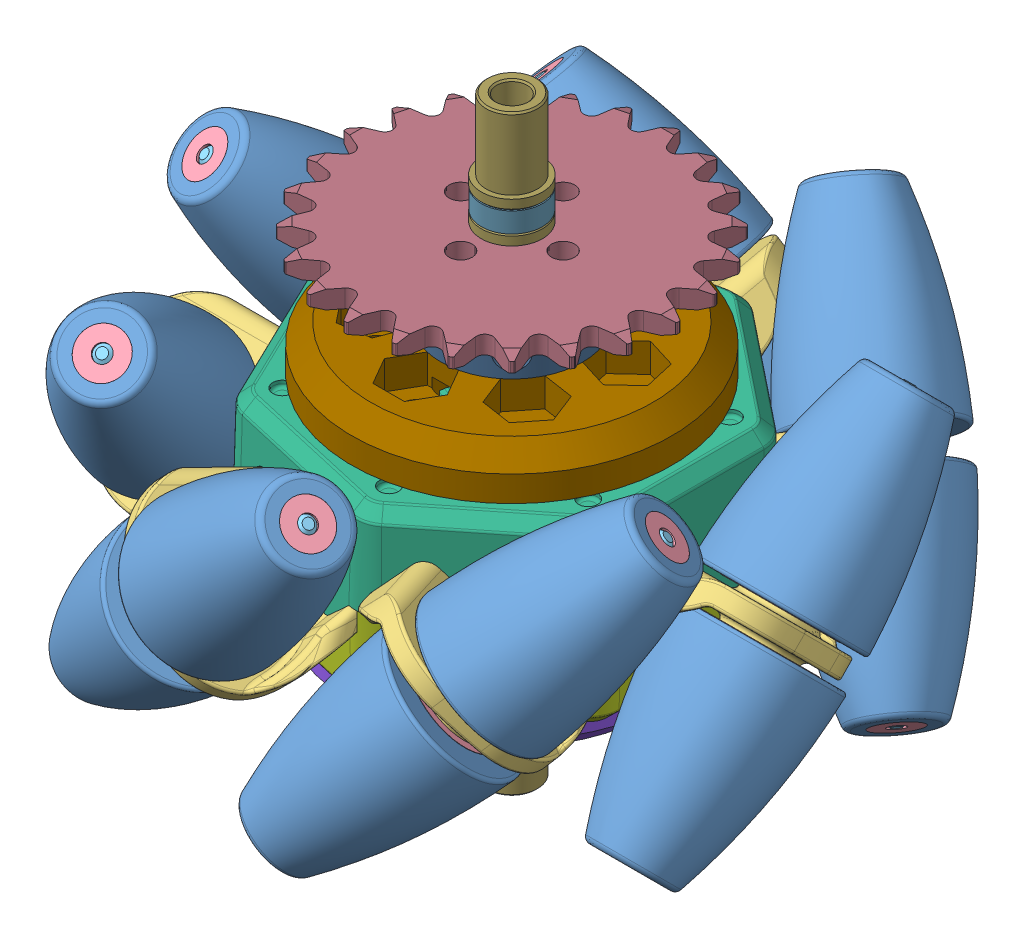
SolidWorks assembly Mecanum Left Assembly, configuration Default. Lengths in mm.
Overall size (116.24 92.45 118.47).
72 component instances, 14 part files, 18 mates.
Components (placement in the parent):
- Mecanum Left-1: Mecanum Left [Default] at (35.1717 68.1525 91.4485) size (116.24 62.26 118.47)
  - Roller-1: Roller [Default] at (-8.8714 -0.1061 -39.3041) x (-0.709843 -0.615883 -0.341777) z (0.144671 0.347402 -0.926489) size (22.31 28.6 22.31)
  - Washer-1: Washer [Default] at (-2.1949 -6.9473 -40.8283) x (-0.689398 -0.707107 0.15726) z (0.68937 -0.707107 -0.15738) size (6 6 6.25)
  - Bracket Left-1: Bracket Left [Default] at origin size (28.34 25.51 28.03)
  - Roller Hub-2: Roller Hub [Default] at (25.0439 -0.1061 31.5645) x (0.446415 -0.698084 -0.559815) z (0.703674 -0.112601 0.701544) size (15.2 28.65 15.2)
  - Pin-1: Pin [Default] at (40.2927 0.0354 -0.0424) x (0.491193 -0.615883 -0.615969) z (0.871051 0.347402 0.34725) size (2.6 61.8 2.6)
  - Roller-3: Roller [Default] at (-36.2516 0.1061 17.5878) x (-0.306866 0.707107 -0.637051) z (-0.900888 0.000087 0.434052) size (22.31 28.6 22.31)
  - Washer-2: Washer [Default] at (19.6895 6.9473 -35.8342) x (-0.552772 -0.707107 -0.440957) z (0.552849 -0.707107 0.44086) size (6 6 6.25)
  - Roller-5: Roller [Default] at (25.1987 -0.1061 -31.441) x (-0.175349 -0.615883 -0.768076) z (0.814571 0.347402 -0.464528) size (22.31 28.6 22.31)
  - Washer-5: Washer [Default] at (-33.2899 -6.9473 -23.7392) x (-0.306866 -0.707107 0.637051) z (0.306754 -0.707107 -0.637104) size (6 6 6.25)
  - Bracket Left-2: Bracket Left [Default] x (0.62347 0 -0.781847) z (0.781847 0 0.62347) size (28.34 25.51 28.03)
  - Pin-2: Pin [Default] at (25.1544 0.0354 31.4763) x (0.787838 -0.615883 0) z (0.271578 0.347402 0.897528) size (2.6 61.8 2.6)
  - Roller-6: Roller [Default] at (-36.3528 0.1061 -17.3777) x (0.306754 0.707107 -0.637104) z (-0.901039 0.000087 -0.433738) size (22.31 28.6 22.31)
  - Washer-6: Washer [Default] at (-15.741 6.9473 -37.7357) x (-0.689398 -0.707107 0.15726) z (0.68937 -0.707107 -0.15738) size (6 6 6.25)
  - Roller-9: Roller [Default] at (40.2927 -0.1061 0.099) x (0.491193 -0.615883 -0.615969) z (0.871051 0.347402 0.34725) size (22.31 28.6 22.31)
  - Washer-8: Washer [Default] at (-39.3157 -6.9473 11.2269) x (0.306754 -0.707107 0.637104) z (-0.306866 -0.707107 -0.637051) size (6 6 6.25)
  - Bracket Left-3: Bracket Left [Default] x (-0.22257 0 -0.974917) z (0.974917 0 -0.22257) size (28.34 25.51 28.03)
  - Bracket Left-4: Bracket Left [Default] x (-0.901001 0 -0.433816) z (0.433816 0 -0.901001) size (28.34 25.51 28.03)
  - Roller Hub-6: Roller Hub [Default] at (-36.2516 0.1061 17.5878) x (-0.446512 0.698084 -0.559737) z (-0.840471 -0.112601 0.530028) size (15.2 28.65 15.2)
  - Roller-10: Roller [Default] at (-9.0782 0.1061 -39.2568) x (0.68937 0.707107 -0.15738) z (-0.222655 0.000087 -0.974897) size (22.31 28.6 22.31)
  - Washer-10: Washer [Default] at (-39.3176 6.9473 -11.2201) x (-0.306866 -0.707107 0.637051) z (0.306754 -0.707107 -0.637104) size (6 6 6.25)
  - Roller-13: Roller [Default] at (25.0439 -0.1061 31.5645) x (0.787838 -0.615883 0) z (0.271578 0.347402 0.897528) size (22.31 28.6 22.31)
  - Washer-11: Washer [Default] at (-15.7344 -6.9473 37.7385) x (0.68937 -0.707107 0.15738) z (-0.689398 -0.707107 -0.15726) size (6 6 6.25)
  - Bracket Left-5: Bracket Left [Default] x (-0.900926 0 0.433974) z (-0.433974 0 -0.900926) size (28.34 25.51 28.03)
  - Roller Hub-8: Roller Hub [Default] at (-36.3437 -0.1061 17.3967) x (0.446512 -0.698084 0.559737) z (-0.840471 -0.112601 0.530028) size (15.2 28.65 15.2)
  - Roller-14: Roller [Default] at (25.0329 0.1061 -31.5732) x (0.552849 0.707107 0.44086) z (0.623402 0.000087 -0.781901) size (22.31 28.6 22.31)
  - Washer-14: Washer [Default] at (-33.2858 6.9473 23.745) x (0.306754 -0.707107 0.637104) z (-0.306866 -0.707107 -0.637051) size (6 6 6.25)
  - Roller Hub-11: Roller Hub [Default] at (25.1987 -0.1061 -31.441) x (-0.645131 -0.698084 -0.310619) z (0.527331 -0.112601 -0.842166) size (15.2 28.65 15.2)
  - Roller Hub-12: Roller Hub [Default] at (25.0329 0.1061 -31.5732) x (0.645131 0.698084 0.310619) z (0.527331 -0.112601 -0.842166) size (15.2 28.65 15.2)
  - Pin-5: Pin [Default] at (-8.9197 0.0354 39.293) x (0.491301 -0.615883 0.615883) z (-0.532275 0.347402 0.772007) size (2.6 61.8 2.6)
  - Washer-15: Washer [Default] at (19.6958 -6.9473 35.8307) x (0.552849 -0.707107 -0.44086) z (-0.552772 -0.707107 0.440957) size (6 6 6.25)
  - Bracket Left-6: Bracket Left [Default] x (-0.222399 0 0.974956) z (-0.974956 0 -0.222399) size (28.34 25.51 28.03)
  - Roller Hub-13: Roller Hub [Default] at (40.2927 -0.1061 0.099) x (-0.159363 -0.698084 -0.698056) z (0.98722 -0.112601 -0.112773) size (15.2 28.65 15.2)
  - Roller Hub-14: Roller Hub [Default] at (-36.3528 0.1061 -17.3777) x (0.159242 0.698084 -0.698084) z (-0.938409 -0.112601 -0.326663) size (15.2 28.65 15.2)
  - Roller-17: Roller [Default] at (40.2927 0.1061 -0.1131) x (0 0.707107 0.707107) z (1 0.000087 -0.000087) size (22.31 28.6 22.31)
  - Washer-17: Washer [Default] at (-2.1877 6.9473 40.8287) x (0.68937 -0.707107 0.15738) z (-0.689398 -0.707107 -0.15726) size (6 6 6.25)
  - Roller Hub-17: Roller Hub [Default] at (40.2927 0.1061 -0.1131) x (0.159363 0.698084 0.698056) z (0.98722 -0.112601 -0.112773) size (15.2 28.65 15.2)
  - Pin-7: Pin [Default] at (-36.2823 0.0354 17.5241) x (-0.175215 -0.615883 0.768107) z (-0.935449 0.347402 0.065166) size (2.6 61.8 2.6)
  - Washer-19: Washer [Default] at (40.2939 -6.9473 6.9403) x (0 -0.707107 -0.707107) z (0.000123 -0.707107 0.707107) size (6 6 6.25)
  - Bracket Left-7: Bracket Left [Default] x (0.623607 0 0.781738) z (-0.781738 0 0.623607) size (28.34 25.51 28.03)
  - Roller Hub-18: Roller Hub [Default] at (-36.2608 -0.1061 -17.5689) x (-0.159242 -0.698084 0.698084) z (-0.938409 -0.112601 -0.326663) size (15.2 28.65 15.2)
  - Roller-20: Roller [Default] at (-9.0576 -0.1061 39.2616) x (0.491301 -0.615883 0.615883) z (-0.532275 0.347402 0.772007) size (22.31 28.6 22.31)
  - Washer-20: Washer [Default] at (30.5578 6.9473 27.1659) x (0.552849 -0.707107 -0.44086) z (-0.552772 -0.707107 0.440957) size (6 6 6.25)
  - Pin-9: Pin [Default] at (-36.3221 0.0354 -17.4414) x (-0.709783 -0.615883 0.341901) z (-0.634175 0.347402 -0.690749) size (2.6 61.8 2.6)
  - Hub Inner Left-1: Hub Inner Left [Default] at origin size (62.26 19.81 61.13)
  - Roller Hub-21: Roller Hub [Default] at (-9.0645 -0.1061 39.26) x (0.716016 -0.698084 0) z (-0.109781 -0.112601 0.987557) size (15.2 28.65 15.2)
  - Roller Hub-22: Roller Hub [Default] at (-8.8577 0.1061 39.3072) x (-0.716016 0.698084 0) z (-0.109781 -0.112601 0.987557) size (15.2 28.65 15.2)
  - Roller Hub-23: Roller Hub [Default] at (-9.0782 0.1061 -39.2568) x (0.645077 0.698084 -0.310732) z (-0.329669 -0.112601 -0.937358) size (15.2 28.65 15.2)
  - Roller-22: Roller [Default] at (-36.3437 -0.1061 17.3967) x (-0.175215 -0.615883 0.768107) z (-0.935449 0.347402 0.065166) size (22.31 28.6 22.31)
  - Washer-23: Washer [Default] at (40.2915 6.9473 -6.9544) x (0 -0.707107 -0.707107) z (0.000123 -0.707107 0.707107) size (6 6 6.25)
  - Roller Hub-24: Roller Hub [Default] at (25.2097 0.1061 31.4322) x (-0.446415 0.698084 0.559815) z (0.703674 -0.112601 0.701544) size (15.2 28.65 15.2)
  - Pin-11: Pin [Default] at (-9.0092 0.0354 -39.2726) x (-0.709843 -0.615883 -0.341777) z (0.144671 0.347402 -0.926489) size (2.6 61.8 2.6)
  - Roller-24: Roller [Default] at (25.2152 0.1061 31.4278) x (-0.552772 0.707107 0.440957) z (0.623675 0.000087 0.781684) size (22.31 28.6 22.31)
  - Roller Hub-27: Roller Hub [Default] at (-8.8714 -0.1061 -39.3041) x (-0.645077 -0.698084 0.310732) z (-0.329669 -0.112601 -0.937358) size (15.2 28.65 15.2)
  - Roller-25: Roller [Default] at (-36.2608 -0.1061 -17.5689) x (-0.709783 -0.615883 0.341901) z (-0.634175 0.347402 -0.690749) size (22.31 28.6 22.31)
  - Washer-26: Washer [Default] at (30.553 -6.9473 -27.1713) x (-0.552772 -0.707107 -0.440957) z (0.552849 -0.707107 0.44086) size (6 6 6.25)
  - Hub Outer Left-1: Hub Outer Left [Default] at origin size (61.9 23.71 60.76)
  - Pin-13: Pin [Default] at (25.0881 0.0354 -31.5291) x (-0.175349 -0.615883 -0.768076) z (0.814571 0.347402 -0.464528) size (2.6 61.8 2.6)
  - Roller-28: Roller [Default] at (-8.8508 0.1061 39.3087) x (-0.689398 0.707107 -0.15726) z (-0.222314 0.000087 0.974975) size (22.31 28.6 22.31)
- Mecanum Hub A-1: Mecanum Hub A [Default] at (35.1717 56.1525 91.4485) x (1 0 0) z (0 -1 0) size (50 50 12)
- Mecanum Hub B-1: Mecanum Hub B [Default] at (35.1717 80.1525 91.4485) x (1 0 0) z (0 -1 0) size (50 50 12)
- Tetrix Axle Hub-1: Tetrix Axle Hub [Default] at (35.1717 89.1525 91.4485) x (1 0 0) z (0 -1 0) size (22.1 22.1 9.5)
  - Tetrix Axle Hub Body-1: Tetrix Axle Hub Body [Default] at origin size (22.1 22.1 9.5)
  - Tetrix Axle Hub Set Screw-1: Tetrix Axle Hub Set Screw [Default] at (6.9308 6.9308 -3.325) x (-0.707107 0.707107 0) z (0 0 1) size (4.83 7.94 4.83)
- Tetrix Axle Hub-2: Tetrix Axle Hub [Default] at (35.1717 47.1525 91.4485) x (1 0 0) z (0 1 0) size (22.1 22.1 9.5)
  - Tetrix Axle Hub Body-1: Tetrix Axle Hub Body [Default] at origin size (22.1 22.1 9.5)
  - Tetrix Axle Hub Set Screw-1: Tetrix Axle Hub Set Screw [Default] at (6.9308 6.9308 -3.325) x (-0.707107 0.707107 0) z (0 0 1) size (4.83 7.94 4.83)
- Tetrix Bushing Bronze-1: Tetrix Bushing Bronze [Default] at (35.1717 40.4025 91.4485) x (-0.837169 0 -0.546944) z (-0.546944 0 0.837169) size (9.56 12.71 9.56)
- Tetrix Bushing Bronze-2: Tetrix Bushing Bronze [Default] at (35.1717 104.3025 91.4485) x (-0.837169 0 -0.546944) z (-0.546944 0 0.837169) size (9.56 12.71 9.56)
- Tetrix Bushing Bronze-3: Tetrix Bushing Bronze [Default] at (35.1717 107.4275 91.4485) x (0.996434 0 -0.084371) z (0.084371 0 0.996434) size (9.56 12.71 9.56)
- Tetrix Sprocket 24T-1: Tetrix Sprocket 24T [Default] at (35.1717 99.9025 91.4485) x (1 0 0) z (0 -1 0) size (52 52 6.8)
- Tetrix Axle Spacer Small-1: Tetrix Axle Spacer Small [Default] at (35.1717 105.865 91.4485) x (1 0 0) z (0 -1 0) size (9.5 9.5 3.12)
Mates (geometry in assembly coordinates):
- Coincident1: coincident anti-aligned: plane of Mecanum Left-1/Hub Inner Left-1 through (35.1717 82.1525 91.4485) normal (0 1 0); plane of Mecanum Hub B-1 through (60.1717 82.1525 91.4485) normal (0 -1 0)
- Concentric1: concentric anti-aligned: cylinder of Mecanum Left-1/Hub Inner Left-1 through (35.1717 82.1525 91.4485) axis (0 -1 0) radius 6; cylinder of Mecanum Hub B-1 through (35.1717 77.1525 91.4485) axis (0 1 0) radius 4.1
- Coincident2: coincident anti-aligned: plane of Mecanum Left-1/Hub Outer Left-1 through (35.1717 54.1525 91.4485) normal (0 -1 0); plane of Mecanum Hub A-1 through (60.1717 54.1525 91.4485) normal (0 1 0)
- Concentric2: concentric aligned: cylinder of Mecanum Left-1/Hub Outer Left-1 through (35.1717 54.1525 91.4485) axis (0 -1 0) radius 6; cylinder of Mecanum Hub A-1 through (35.1717 59.1525 91.4485) axis (0 -1 0) radius 4.1
- Coincident3: coincident anti-aligned: plane of Mecanum Hub B-1 through (35.1717 89.1525 91.4485) normal (0 1 0); plane of Tetrix Axle Hub-1/Tetrix Axle Hub Body-1 through (35.1717 89.1525 91.4485) normal (0 -1 0)
- Concentric3: concentric aligned: cylinder of Mecanum Hub B-1 through (35.1717 77.1525 91.4485) axis (0 1 0) radius 4.1; cylinder of Tetrix Axle Hub-1/Tetrix Axle Hub Body-1 through (35.1717 86.4025 91.4485) axis (0 1 0) radius 2.4375
- Coincident4: coincident anti-aligned: plane of Mecanum Hub A-1 through (35.1717 47.1525 91.4485) normal (0 -1 0); plane of Tetrix Axle Hub-2/Tetrix Axle Hub Body-1 through (35.1717 47.1525 91.4485) normal (0 1 0)
- Concentric4: concentric anti-aligned: cylinder of Mecanum Hub A-1 through (35.1717 59.1525 91.4485) axis (0 -1 0) radius 4.1; cylinder of Tetrix Axle Hub-2/Tetrix Axle Hub Body-1 through (35.1717 47.1525 91.4485) axis (0 1 0) radius 11.05
- Coincident5: coincident anti-aligned: plane of Tetrix Axle Hub-2/Tetrix Axle Hub Body-1 through (35.1717 40.4025 91.4485) normal (0 -1 0); plane of Tetrix Bushing Bronze-1 through (39.1733 40.4025 94.0629) normal (0 1 0)
- Concentric5: concentric aligned: cylinder of Tetrix Axle Hub-2/Tetrix Axle Hub Body-1 through (35.1717 47.1525 91.4485) axis (0 1 0) radius 11.05; cylinder of Tetrix Bushing Bronze-1 through (35.1717 40.4025 91.4485) axis (0 1 0) radius 4
- Concentric9: concentric anti-aligned: cylinder of Tetrix Bushing Bronze-2 through (35.1717 104.3025 91.4485) axis (0 1 0) radius 2.375; cylinder of Tetrix Bushing Bronze-3 through (35.1717 107.4275 91.4485) axis (0 -1 0) radius 4
- Coincident10: coincident anti-aligned: plane of Tetrix Axle Hub-1/Tetrix Axle Hub Body-1 through (35.1717 95.9025 91.4485) normal (0 1 0); plane of Tetrix Sprocket 24T-1 through (35.1717 95.9025 91.4485) normal (0 -1 0)
- Concentric10: concentric aligned: cylinder of Tetrix Axle Hub-1/Tetrix Axle Hub Body-1 through (35.1717 89.1525 91.4485) axis (0 -1 0) radius 11.05; cylinder of Tetrix Sprocket 24T-1 through (35.1717 102.7025 91.4485) axis (0 -1 0) radius 4
- Coincident11: coincident anti-aligned: plane of Tetrix Bushing Bronze-2 through (38.5204 102.7025 93.6363) normal (0 -1 0); plane of Tetrix Sprocket 24T-1 through (35.1717 102.7025 115.7735) normal (0 1 0)
- Concentric11: concentric anti-aligned: cylinder of Tetrix Bushing Bronze-2 through (35.1717 104.3025 91.4485) axis (0 1 0) radius 4; cylinder of Tetrix Sprocket 24T-1 through (35.1717 102.7025 91.4485) axis (0 -1 0) radius 4
- Concentric12: concentric anti-aligned: cylinder of Tetrix Bushing Bronze-2 through (35.1717 104.3025 91.4485) axis (0 1 0) radius 2.375; cylinder of Tetrix Axle Spacer Small-1 through (35.1717 107.4275 91.4485) axis (0 -1 0) radius 2.5
- Coincident12: coincident aligned: plane of Tetrix Bushing Bronze-2 through (39.1733 104.3025 94.0629) normal (0 1 0); circle of Tetrix Axle Spacer Small-1
- Coincident13: coincident anti-aligned: plane of Tetrix Bushing Bronze-3 through (30.4087 107.4275 91.8518) normal (0 -1 0); plane of Tetrix Axle Spacer Small-1 through (35.1717 107.4275 91.4485) normal (0 1 0)
